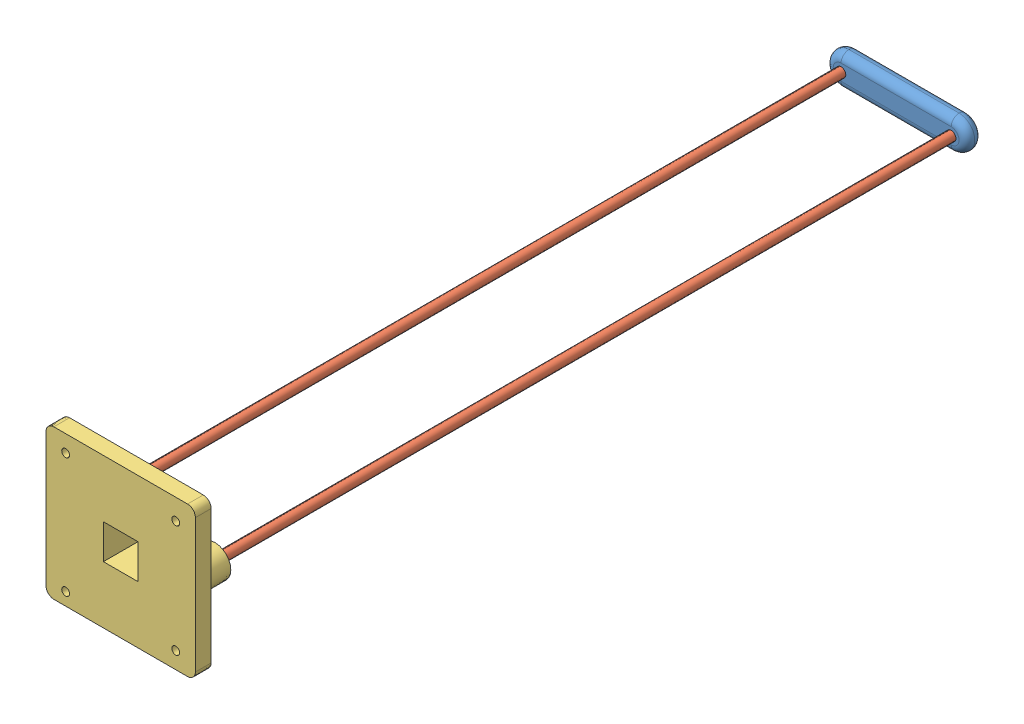
SolidWorks assembly ROCO318 main, configuration Default. Lengths in mm.
Overall size (190 190 1006).
4 component instances, 3 part files, 9 mates.
Components (placement in the parent):
- ROCO318 top extruded-1: ROCO318 top extruded [Default] at origin size (180 40 20)
- ROCO318 SMOOTH ROD-1: ROCO318 SMOOTH ROD [Default] at (-70 0 3) size (12 12 1000)
- ROCO318 SMOOTH ROD-2: ROCO318 SMOOTH ROD [Default] at (70 0 3) size (12 12 1000)
- ROCO318 bottom extruded-1: ROCO318 bottom extruded [Default] at (0 0 1006) x (1 0 0) z (0 0 -1) size (190 190 80)
Mates (geometry in assembly coordinates):
- Coincident1: coincident anti-aligned: plane of ROCO318 top extruded-1 through (-70 0 3) normal (0 0 1); plane of ROCO318 SMOOTH ROD-1 through (-70 0 3) normal (0 0 -1)
- Coincident2: coincident anti-aligned: plane of ROCO318 top extruded-1 through (-70 0 3) normal (0 0 1); plane of ROCO318 SMOOTH ROD-1 through (-70 0 3) normal (0 0 -1)
- Coincident3: coincident anti-aligned: plane of ROCO318 top extruded-1 through (-70 0 3) normal (0 0 1); plane of ROCO318 SMOOTH ROD-1 through (-70 0 3) normal (0 0 -1)
- Concentric1: concentric aligned: cylinder of ROCO318 top extruded-1 through (-70 0 20) axis (0 0 -1) radius 6; cylinder of ROCO318 SMOOTH ROD-1 through (-70 0 1003) axis (0 0 -1) radius 6
- Coincident4: coincident anti-aligned: circle of ROCO318 top extruded-1; cylinder of ROCO318 SMOOTH ROD-2 through (70 0 1003) axis (0 0 -1) radius 6
- Concentric2: concentric aligned: cylinder of ROCO318 top extruded-1 through (70 0 20) axis (0 0 -1) radius 6; cylinder of ROCO318 SMOOTH ROD-2 through (70 0 1003) axis (0 0 -1) radius 6
- Coincident6: coincident anti-aligned: plane of ROCO318 top extruded-1 through (70 0 3) normal (0 0 1); plane of ROCO318 SMOOTH ROD-2 through (70 0 3) normal (0 0 -1)
- Coincident7: coincident anti-aligned: plane of ROCO318 SMOOTH ROD-2 through (70 0 1003) normal (0 0 1); plane of ROCO318 bottom extruded-1 through (70 0 1003) normal (0 0 -1)
- Concentric3: concentric anti-aligned: cylinder of ROCO318 SMOOTH ROD-2 through (70 0 1003) axis (0 0 -1) radius 6; cylinder of ROCO318 bottom extruded-1 through (70 0 956) axis (0 0 1) radius 6
